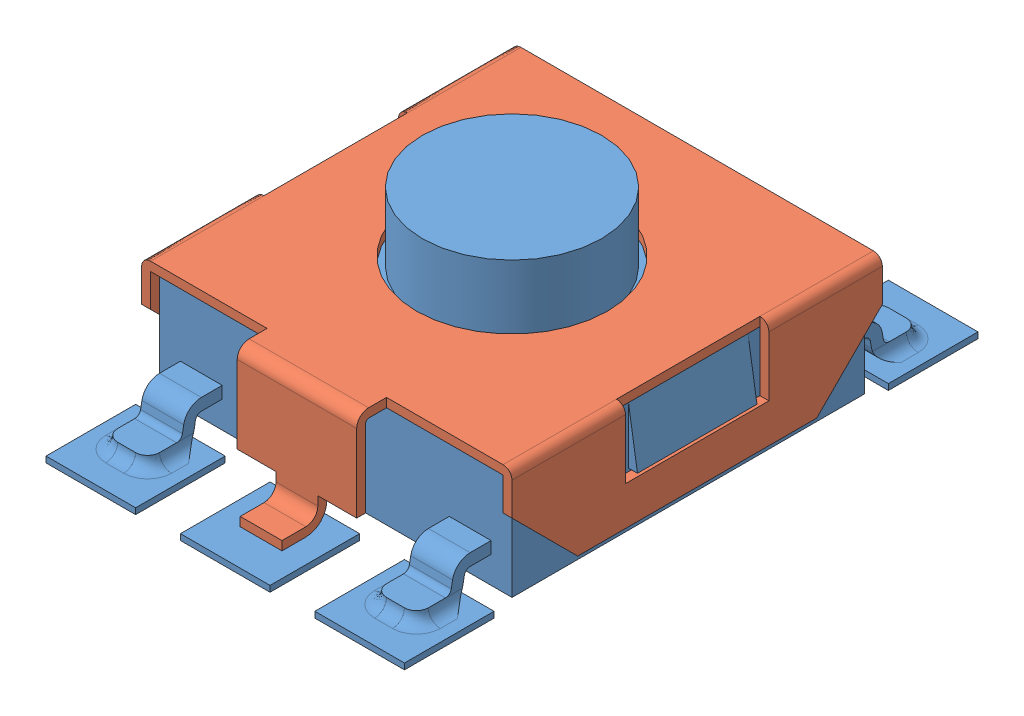
SolidWorks assembly RESET BUTTON, configuration Default. Lengths in mm.
Overall size (6.2 3.1 9.6).
2 component instances, 2 part files, 6 mates.
Components (placement in the parent):
- RESET CORE-1: RESET CORE [Default] at (0 0.1 0) x (-1 0 0) z (0 0 -1) size (6.2 3.1 9.6)
- RESET-1: RESET [Default] at (0 0.1 0) x (0 0 1) z (-1 0 0) size (7.3 2 6.2)
Mates (geometry in assembly coordinates):
- Coincident4: coincident anti-aligned: plane of RESET CORE-1 through (0 0.1 0) normal (0 0 -1); plane of assembly through (0 0 0) normal (0 0 1)
- Coincident5: coincident anti-aligned: plane of RESET CORE-1 through (0 0.1 0) normal (-1 0 0); plane of assembly through (0 0 0) normal (1 0 0)
- Coincident6: coincident anti-aligned: plane of RESET CORE-1 through (0 0 0) normal (0 -1 0); plane of assembly through (0 0 0) normal (0 1 0)
- Coincident7: coincident: plane of assembly through (0 0 0) normal (0 0 1); plane of RESET-1 through (0 0.1 0) normal (0 0 1); plane of assembly
- Coincident9: coincident anti-aligned: plane of RESET-1 through (0 0.1 0) normal (-1 0 0); plane of assembly through (0 0 0) normal (1 0 0)
- Coincident10: coincident aligned: plane of RESET CORE-1 through (0 0.1 0) normal (0 1 0); plane of RESET-1 through (0 0.1 0) normal (0 1 0)
